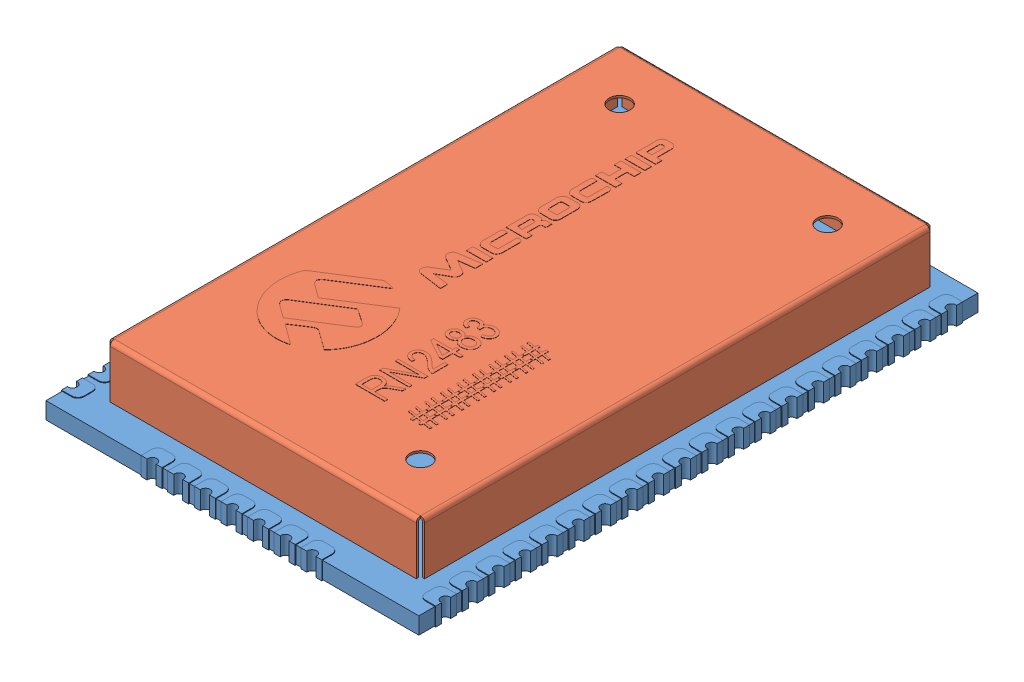
SolidWorks assembly RN2483, configuration Default. Lengths in mm.
Overall size (17.85 3.34 26.7).
2 component instances, 2 part files, 6 mates.
Components (placement in the parent):
- RN2483-PCB-1: RN2483-PCB [Default] at (0 0.035 0) size (17.85 0.87 26.7)
- RN2483-CAN-1: RN2483-CAN [Default] at (0 3.235 -0.385) x (-1 0 0) z (0 0 1) size (15 2.51 24.5)
Mates (geometry in assembly coordinates):
- Coincident1: coincident anti-aligned: plane of RN2483-PCB-1 through (3.6 0 12.875) normal (0 -1 0); plane of assembly through (0 0 0) normal (0 1 0)
- Symmetric1: symmetric aligned: plane of RN2483-PCB-1 through (8.89 0.835 -13.335) normal (1 0 0); plane of RN2483-PCB-1 through (-8.89 0.835 -13.335) normal (-1 0 0); plane of assembly through (0 0 0) normal (1 0 0)
- Symmetric2: symmetric aligned: plane of RN2483-PCB-1 through (-8.89 0.835 13.335) normal (0 0 1); plane of RN2483-PCB-1 through (-8.89 0.835 -13.335) normal (0 0 -1); plane of assembly through (0 0 0) normal (0 0 1)
- Coincident2: coincident anti-aligned: plane of RN2483-PCB-1 through (0 0.835 0) normal (0 1 0); plane of RN2483-CAN-1 through (-7.5 0.835 11.665) normal (0 -1 0)
- Width1: width aligned: plane of RN2483-CAN-1 through (7.5 3.235 -0.385) normal (1 0 0); plane of RN2483-CAN-1 through (-7.5 3.235 -0.385) normal (-1 0 0); plane of RN2483-PCB-1 through (8.89 0.835 -13.335) normal (1 0 0); plane of RN2483-PCB-1 through (-8.89 0.835 -13.335) normal (-1 0 0)
- Distance1: distance = 0.7 mm aligned: plane of RN2483-CAN-1 through (0 3.235 -12.635) normal (0 0 -1); plane of RN2483-PCB-1 through (-8.89 0.835 -13.335) normal (0 0 -1)
